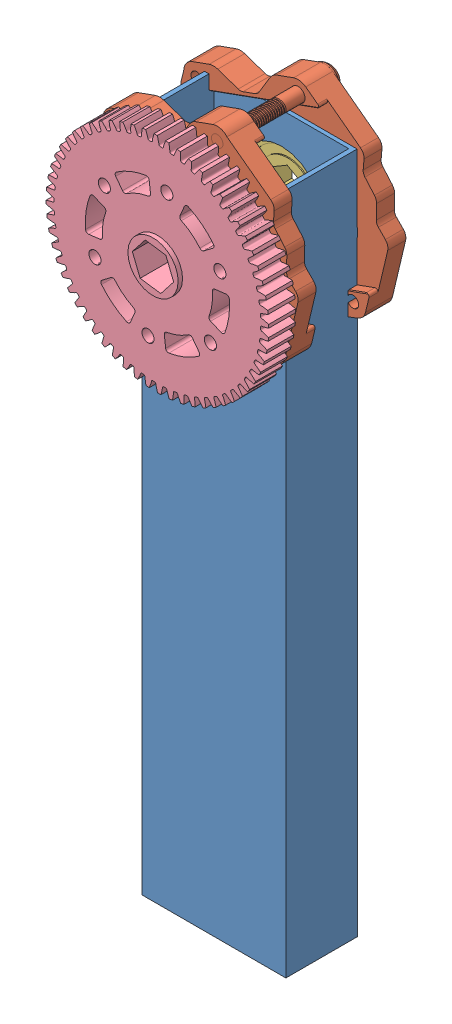
SolidWorks assembly left_arm_assemble, configuration Default. Lengths in mm.
Overall size (88.92 260.37 55.84).
5 component instances, 4 part files, 6 mates.
Components (placement in the parent):
- intake_arm_right_and_left-1: intake_arm_right_and_left [Default] at (8.4508 7.1726 213.9849) size (50.8 241.3 25.4)
- VEX-217-3432-1: VEX-217-3432 [Default] at (18.0715 224.5657 221.8389) x (-0.940521 -0.339736 0) z (0 0 -1) size (69.4 66.32 40.87)
- VEX-217-3875-1: VEX-217-3875 [Default] at (18.6108 223.0726 235.2889) x (0.990166 -0.139899 0) z (-0.139899 -0.990166 0) size (31.12 7.94 31.12)
- VEX-217-3875-2: VEX-217-3875 [Default] at (18.6108 223.0726 208.3889) x (-0.861056 -0.50851 0) z (0.50851 -0.861056 0) size (31.12 7.94 31.12)
- VEX-217-2714-1: VEX-217-2714 [Default] at (18.5587 223.0516 249.551) x (-0.139899 -0.990166 0) z (0 0 -1) size (78.68 78.68 12.65)
Mates (geometry in assembly coordinates):
- Concentric7: concentric anti-aligned: circle of intake_arm_right_and_left-1; circle of VEX-217-3432-1
- Coincident1: coincident aligned: circle of VEX-217-3432-1; circle of VEX-217-3875-1
- Coincident2: coincident aligned: circle of VEX-217-3432-1; circle of VEX-217-3875-2
- Coincident8: coincident anti-aligned: plane of VEX-217-3875-1 through (24.8984 222.1843 243.2264) normal (0 0 1); plane of VEX-217-2714-1 through (18.5587 223.0516 243.2264) normal (0 0 -1)
- Coincident9: coincident aligned: line of VEX-217-3875-1 through (21.3569 216.2615 243.2264) axis (0.616239 0.787559 0); line of VEX-217-2714-1 through (21.3169 216.2104 243.2264) axis (0.616239 0.787559 0)
- Coincident10: coincident aligned: line of VEX-217-3875-1 through (23.1364 228.8564 243.2264) axis (-0.990166 0.139899 0); line of VEX-217-2714-1 through (23.1043 228.8609 243.2264) axis (-0.990166 0.139899 0)
